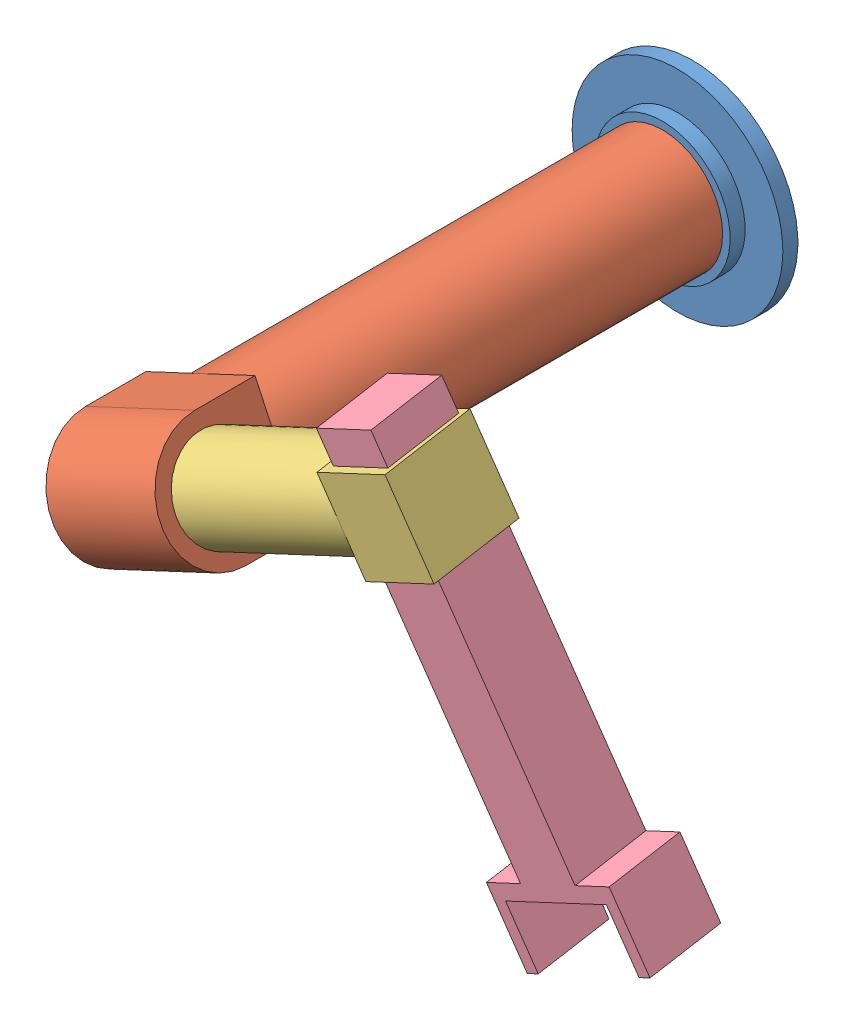
SolidWorks assembly koncept, configuration Domyślna. Lengths in mm.
Overall size (385.36 313.34 390).
4 component instances, 4 part files, 7 mates.
Components (placement in the parent):
- podstawa_koncept-1: podstawa_koncept [Domyślna] at (-0.7782 -3.352 90) size (140 140 20)
- c1_koncept-1: c1_koncept [Domyślna] at (-0.7782 -3.352 100) x (-0.905612 -0.424108 0) z (0 0 1) size (80 80 380)
- c2_koncept-1: c2_koncept [Domyślna] at (-37.0026 -20.3164 440) x (-0.420959 0.898886 0.121646) z (0.905612 0.424108 0) size (60 60 250)
- c3_koncept-1: c3_koncept [Domyślna] at (146.249 121.353 445.3183) x (-0.905612 -0.424108 0) z (0.420959 -0.898886 -0.121646) size (90 50 300)
Mates (geometry in assembly coordinates):
- Równolegle2: parallel anti-aligned: plane of podstawa_koncept-1 through (-0.7782 -3.352 100) normal (0 0 1); plane of c1_koncept-1 through (-0.7782 -3.352 100) normal (0 0 -1)
- Wspólnie3: coincident anti-aligned: plane of podstawa_koncept-1 through (-0.7782 -3.352 100) normal (0 0 1); plane of c1_koncept-1 through (-0.7782 -3.352 100) normal (0 0 -1)
- Koncentryczne1: concentric anti-aligned: cylinder of podstawa_koncept-1 through (-0.7782 -3.352 100) axis (0 0 1) radius 40; cylinder of c1_koncept-1 through (-0.7782 -3.352 400) axis (0 0 -1) radius 40
- Prostopadle3: perpendicular: plane of c2_koncept-1 through (163.4611 37.4416 460.2975) normal (-0.051591 0.110164 -0.992574); plane of c3_koncept-1 through (146.249 121.353 445.3183) normal (-0.420959 0.898886 0.121646)
- Wspólnie7: coincident anti-aligned: plane of c2_koncept-1 through (163.4611 37.4416 460.2975) normal (-0.051591 0.110164 -0.992574); plane of c3_koncept-1 through (234.6662 -114.6048 439.7211) normal (0.051591 -0.110164 0.992574)
- Wspólnie8: coincident anti-aligned: plane of c2_koncept-1 through (199.6856 54.4059 460.2975) normal (-0.905612 -0.424108 0); plane of c3_koncept-1 through (268.3111 -92.1323 390.0924) normal (0.905612 0.424108 0)
- Wspólnie9: coincident anti-aligned: circle of c1_koncept-1; circle of c2_koncept-1
